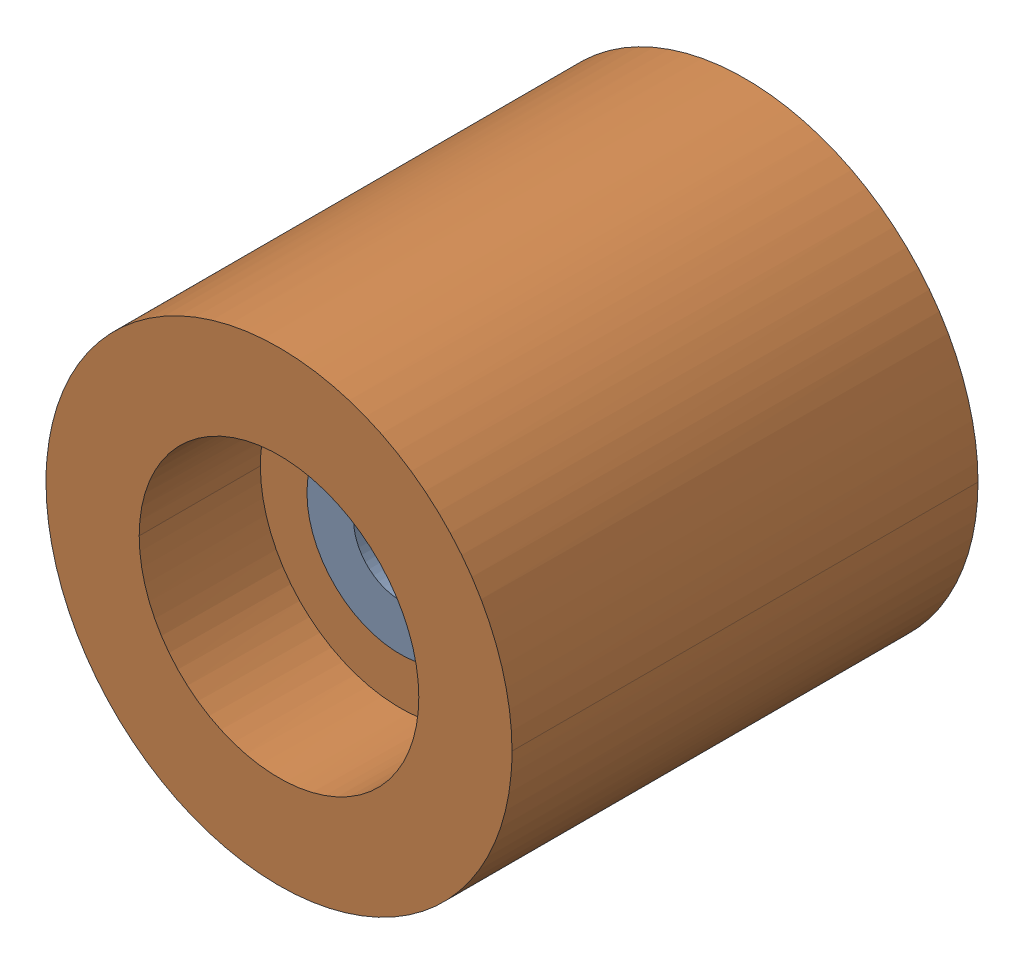
SolidWorks assembly Oil Bearing, configuration 默认. Lengths in mm.
Overall size (5 5.03 5).
4 component instances, 3 part files, 0 mates.
Components (placement in the parent):
- Bearing gasket-1: Bearing gasket [默认] at (0 0 -1.3) size (2 2.01 0.5)
- Bearing-1: Bearing [默认] at origin size (5 5.03 5)
- Oil-1: Oil [默认] at (0 0 -4.5) size (4 4 2.7)
- Bearing gasket-2: Bearing gasket [默认] at (0 0 -4.5) size (2 2.01 0.5)
